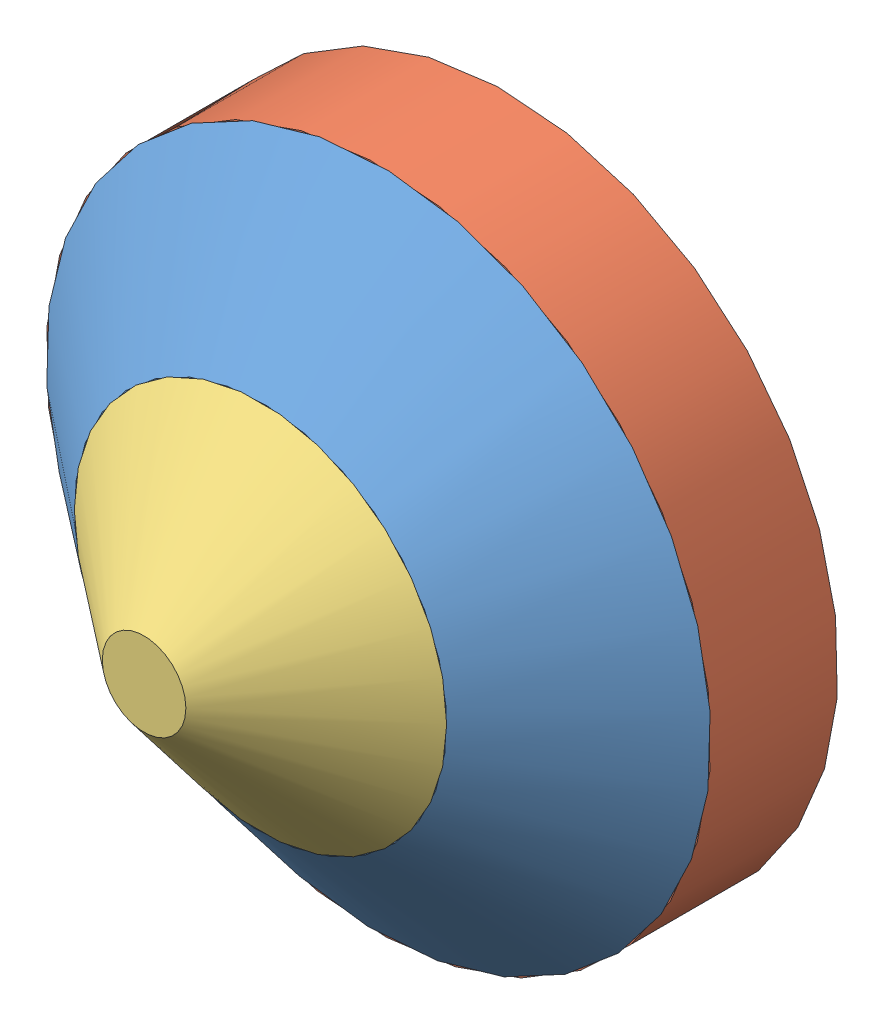
SolidWorks assembly ETA_1, configuration Default. Lengths in mm.
Overall size (346.61 346.61 139.2).
3 component instances, 3 part files, 4 mates.
Components (placement in the parent):
- Bi_1-1: Bi_1 [Default] at (16.2169 49.8318 114.065) x (-0.881209 -0.472727 0) z (0 0 1) size (256 256 45.4)
- Bi_2-1: Bi_2 [Default] at (16.2169 49.8318 114.065) x (-0.943147 -0.332376 0) z (0 0 -1) size (256 256 49)
- W-2: W [Default] at (16.2169 49.8318 159.465) size (143.34 143.34 44.8)
Mates (geometry in assembly coordinates):
- Coincident4: coincident anti-aligned: plane of Bi_1-1 through (16.2169 49.8318 114.065) normal (0 0 -1); plane of Bi_2-1 through (16.2169 49.8318 114.065) normal (0 0 1)
- Concentric2: concentric anti-aligned: circle of Bi_1-1; circle of Bi_2-1
- Coincident5: coincident: plane of Bi_1-1 through (16.2169 49.8318 159.465) normal (0 0 1); plane of W-2 through (16.2169 49.8318 159.465) normal (0 0 -1)
- Concentric3: concentric aligned: circle of Bi_1-1; circle of W-2
